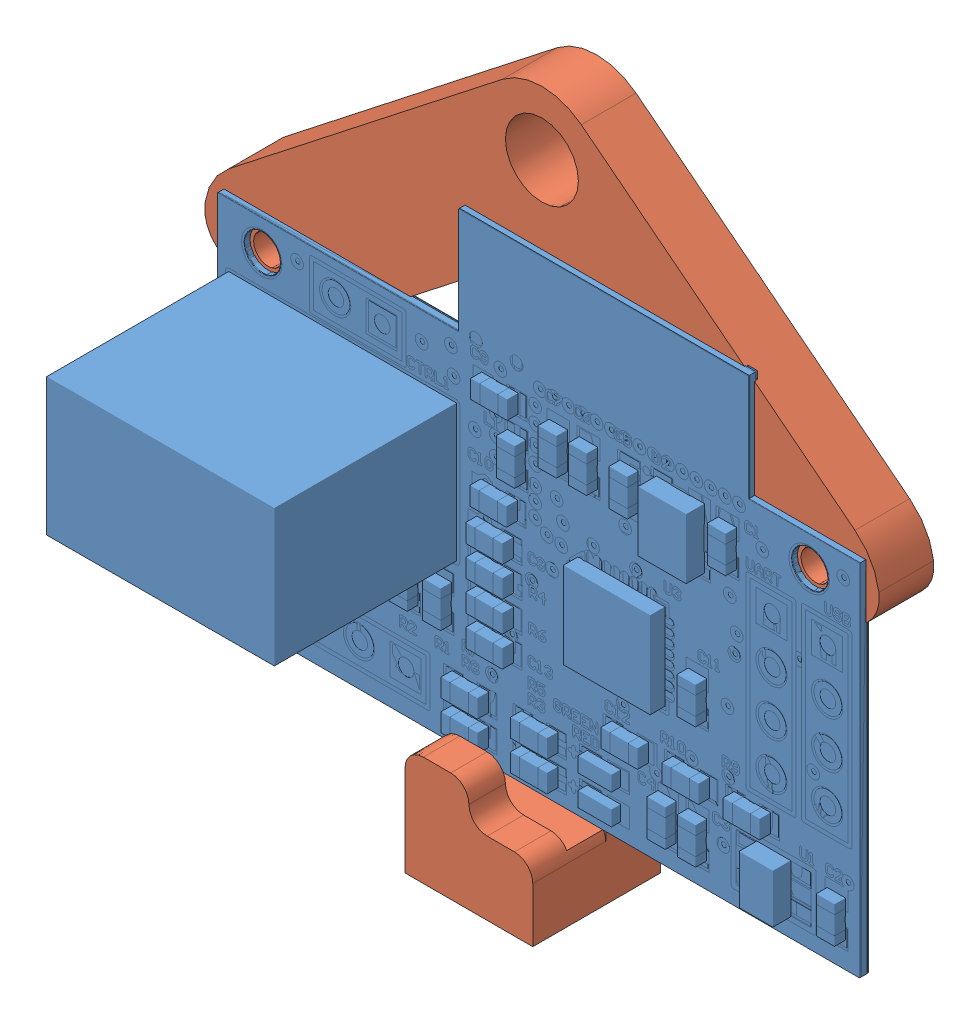
SolidWorks assembly ESP32C3_REMOTE_SW_SHELL, configuration 默认. Lengths in mm.
Overall size (36.97 37.09 13.35).
2 component instances, 2 part files, 3 mates.
Components (placement in the parent):
- ESP32C3_REMOTE_SWITCH_PCB-1: ESP32C3_REMOTE_SWITCH_PCB [默认] at origin size (35.18 25.53 10.54)
- ESP32C3_REMOTE_SWITCH_SHELL-1: ESP32C3_REMOTE_SWITCH_SHELL [默认] at (9.3946 0.2263 -3.4) size (36.97 37.09 7)
Mates (geometry in assembly coordinates):
- 同心1: concentric anti-aligned: circle of ESP32C3_REMOTE_SWITCH_PCB-1; circle of ESP32C3_REMOTE_SWITCH_SHELL-1
- 同心2: concentric anti-aligned: circle of ESP32C3_REMOTE_SWITCH_PCB-1; circle of ESP32C3_REMOTE_SWITCH_SHELL-1
- 重合1: coincident aligned: circle of ESP32C3_REMOTE_SWITCH_PCB-1; plane of ESP32C3_REMOTE_SWITCH_SHELL-1 through (-15.1675 5.2581 -0.4) normal (0 0 1)
